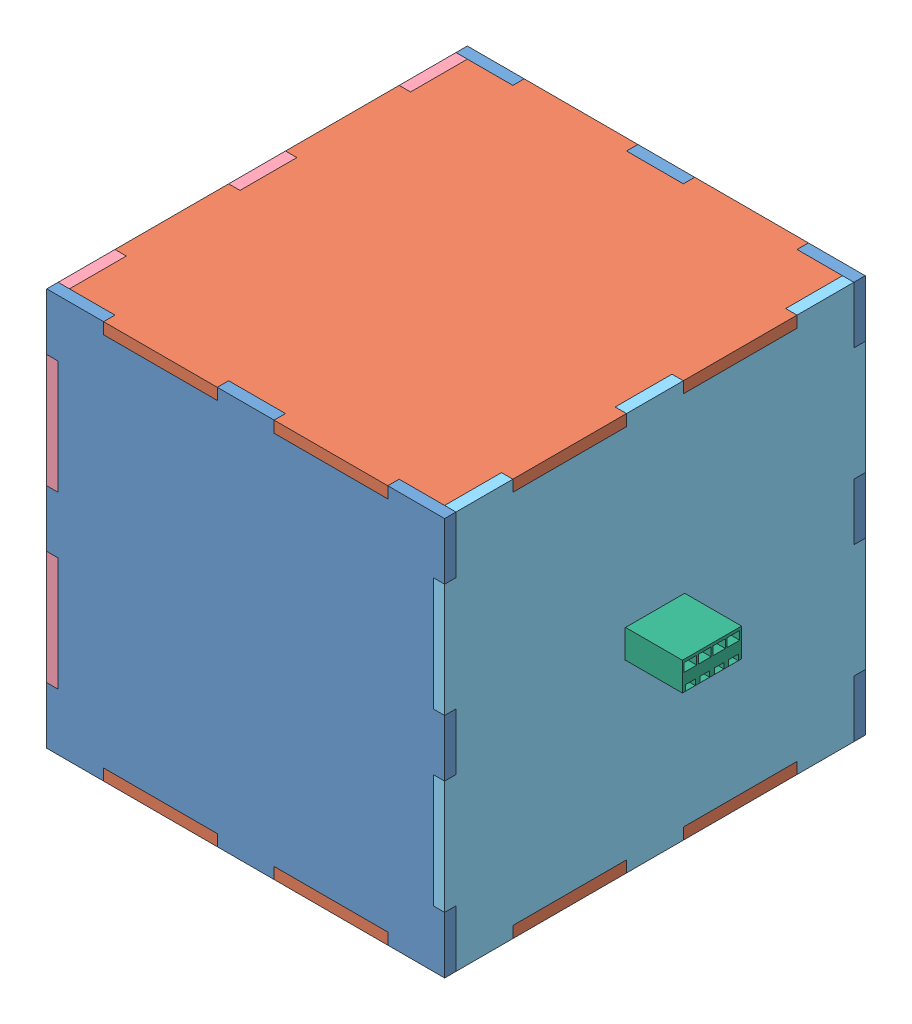
SolidWorks assembly Module_Assem, configuration Default. Lengths in mm.
Overall size (80 70 74).
12 component instances, 7 part files, 21 mates.
Components (placement in the parent):
- Module_Front-1: Module_Front [Default] at (-38.8904 -9.0649 78.7698) size (70 70 2)
- Module_TB-1: Module_TB [Default] at (-38.8904 23.9351 41.7698) x (1 0 0) z (0 1 0) size (70 74 2)
- fixer-1: fixer [Default] at (-10.8904 -42.0649 11.7698) size (10 10 10)
- fixer-2: fixer [Default] at (-66.8904 -42.0649 11.7698) size (10 10 10)
- fixer-3: fixer [Default] at (-66.8904 -42.0649 71.7698) size (10 10 10)
- fixer-4: fixer [Default] at (-10.8904 -42.0649 71.7698) size (10 10 10)
- Module_LR_Female-1: Module_LR_Female [Default] at (-73.8904 -9.0649 41.7698) x (0 0 1) z (-1 0 0) size (74 70 2)
- Module_LR_Male-1: Module_LR_Male [Default] at (-3.8904 -9.0649 41.7698) x (0 0 -1) z (1 0 0) size (74 70 2)
- Module_Front-3: Module_Front [Default] at (-38.8904 -9.0649 6.7698) size (70 70 2)
- Module_TB-3: Module_TB [Default] at (-38.8904 -44.0649 41.7698) x (1 0 0) z (0 1 0) size (70 74 2)
- port_1-1: port_1 [Default] at (-5.8904 -6.7008 48.1338) x (0 0 -1) z (1 0 0) size (10.41 5 12)
- port_2-1: port_2 [Default] at (-73.8904 -5.5649 35.3198) x (0 0 1) z (-1 0 0) size (12.53 7.1 20.5)
Mates (geometry in assembly coordinates):
- Coincident10: coincident aligned: plane of Module_Front-1 through (-73.8904 25.9351 76.7698) normal (0 1 0); plane of Module_TB-1 through (-38.8904 25.9351 41.7698) normal (0 1 0)
- Coincident11: coincident aligned: plane of Module_Front-1 through (-38.8904 -9.0649 78.7698) normal (0 0 1); plane of Module_TB-1 through (-38.8904 25.9351 78.7698) normal (0 0 1)
- Coincident21: coincident anti-aligned: plane of Module_Front-1 through (-38.8904 -9.0649 76.7698) normal (0 0 -1); plane of fixer-3 through (-71.8904 -32.0649 76.7698) normal (0 0 1)
- Coincident26: coincident anti-aligned: plane of Module_Front-1 through (-38.8904 -9.0649 76.7698) normal (0 0 -1); plane of fixer-4 through (-15.8904 -32.0649 76.7698) normal (0 0 1)
- Coincident30: coincident aligned: plane of Module_Front-1 through (-38.8904 -9.0649 78.7698) normal (0 0 1); plane of Module_LR_Female-1 through (-71.8904 -9.0649 78.7698) normal (0 0 1)
- Coincident34: coincident aligned: plane of Module_TB-1 through (-38.8904 25.9351 41.7698) normal (0 1 0); plane of Module_LR_Female-1 through (-71.8904 25.9351 6.7698) normal (0 1 0)
- Coincident35: coincident anti-aligned: plane of Module_Front-1 through (-71.8904 -9.0649 76.7698) normal (-1 0 0); plane of Module_LR_Female-1 through (-71.8904 -9.0649 41.7698) normal (1 0 0)
- Coincident37: coincident anti-aligned: plane of Module_Front-1 through (-5.8904 -9.0649 76.7698) normal (1 0 0); plane of Module_LR_Male-1 through (-5.8904 -9.0649 41.7698) normal (-1 0 0)
- Coincident39: coincident aligned: plane of Module_TB-1 through (-38.8904 25.9351 41.7698) normal (0 1 0); plane of Module_LR_Male-1 through (-5.8904 25.9351 76.7698) normal (0 1 0)
- Coincident41: coincident anti-aligned: plane of Module_TB-1 through (-71.8904 25.9351 6.7698) normal (0 0 -1); plane of Module_Front-3 through (-38.8904 -9.0649 6.7698) normal (0 0 1)
- Coincident42: coincident aligned: plane of Module_LR_Female-1 through (-73.8904 -9.0649 41.7698) normal (-1 0 0); plane of Module_Front-3 through (-73.8904 -44.0649 4.7698) normal (-1 0 0)
- Coincident43: coincident aligned: plane of Module_TB-1 through (-38.8904 25.9351 41.7698) normal (0 1 0); plane of Module_Front-3 through (-73.8904 25.9351 4.7698) normal (0 1 0)
- Coincident44: coincident aligned: plane of Module_LR_Male-1 through (-3.8904 -9.0649 41.7698) normal (1 0 0); plane of Module_TB-3 through (-3.8904 -42.0649 41.7698) normal (1 0 0)
- Coincident45: coincident aligned: plane of Module_Front-3 through (-38.8904 -9.0649 4.7698) normal (0 0 -1); plane of Module_TB-3 through (-38.8904 -42.0649 4.7698) normal (0 0 -1)
- Coincident46: coincident aligned: plane of Module_Front-3 through (-73.8904 -44.0649 4.7698) normal (0 -1 0); plane of Module_TB-3 through (-38.8904 -44.0649 41.7698) normal (0 -1 0)
- Coincident51: coincident anti-aligned: plane of Module_LR_Female-1 through (-63.8904 -5.5649 35.3198) normal (0 -1 0); plane of port_2-1 through (-64.8904 -5.5649 35.3198) normal (0 1 0)
- Coincident52: coincident anti-aligned: plane of Module_LR_Female-1 through (-63.8904 -12.5649 35.3198) normal (0 0 1); plane of port_2-1 through (-64.8904 -5.5649 35.3198) normal (0 0 -1)
- Coincident53: coincident aligned: plane of Module_LR_Female-1 through (-73.8904 -9.0649 41.7698) normal (-1 0 0); plane of port_2-1 through (-73.8904 -5.5649 35.3198) normal (-1 0 0)
- Coincident54: coincident anti-aligned: plane of Module_LR_Male-1 through (-13.8904 -6.5649 47.0098) normal (0 -1 0); plane of port_1-1 through (6.1096 -6.5649 46.9398) normal (0 1 0)
- Coincident55: coincident anti-aligned: plane of Module_LR_Male-1 through (-13.8904 -11.5649 36.5298) normal (0 0 1); plane of port_1-1 through (6.1096 -6.5649 36.5298) normal (0 0 -1)
- Coincident56: coincident aligned: plane of Module_LR_Male-1 through (-5.8904 -9.0649 41.7698) normal (-1 0 0); plane of port_1-1 through (-5.8904 -6.7008 48.1338) normal (-1 0 0)
